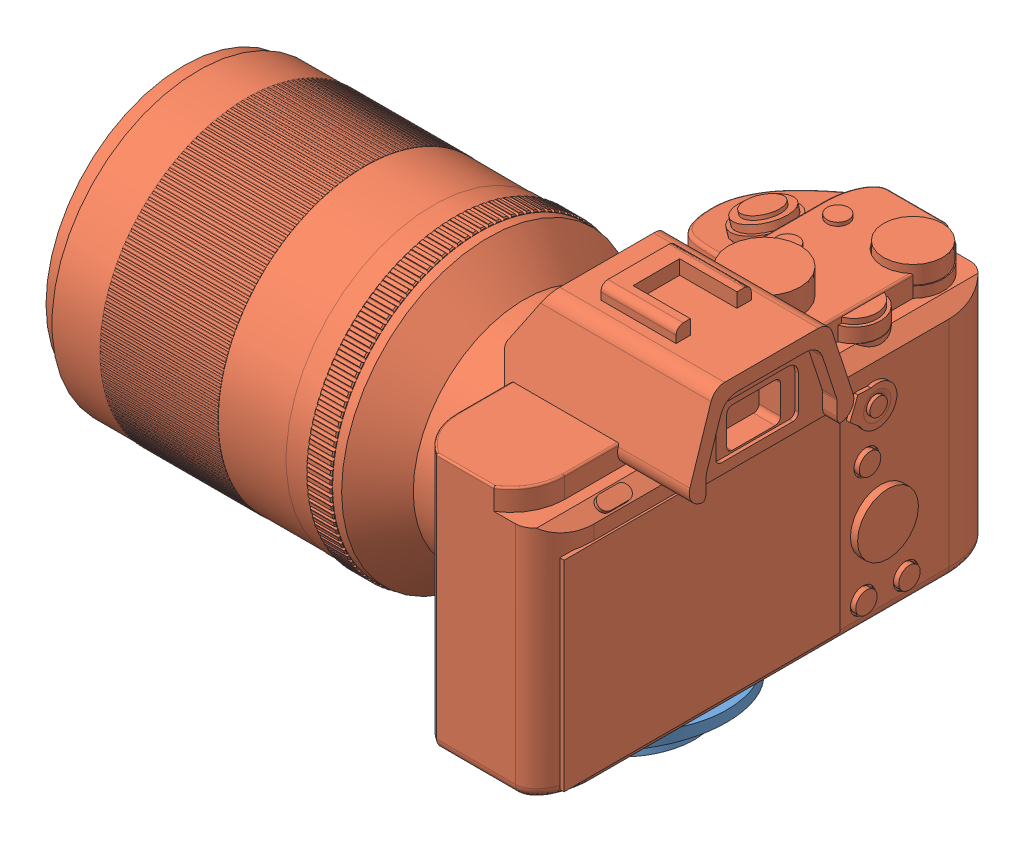
SolidWorks assembly bar3, configuration 默认. Lengths in mm.
Overall size (164 112.91 132.15).
2 component instances, 2 part files, 3 mates.
Components (placement in the parent):
- bar31-1: bar31 [默认] at (2.5673 -11.8834 50) size (50 16.91 50)
- sony-1: sony [默认] at (2.5673 8.1166 50) x (0 0 -1) z (1 0 0) size (132.15 97.5 164)
Mates (geometry in assembly coordinates):
- 重合1: coincident anti-aligned: plane of bar31-1 through (2.5673 8.1166 50) normal (0 1 0); plane of sony-1 through (2.5673 8.1166 50) normal (0 -1 0)
- 同心1: concentric aligned: cylinder of bar31-1 through (2.5673 8.1166 50) axis (0 -1 0) radius 25; cylinder of sony-1 through (2.5673 20.1166 50) axis (0 -1 0) radius 2.5
- 平行1: parallel: plane of bar31-1 through (2.5673 -11.8834 50) normal (1 0 0); line of sony-1 through (-9.9327 11.1166 9.1697) axis (0 0 1)
